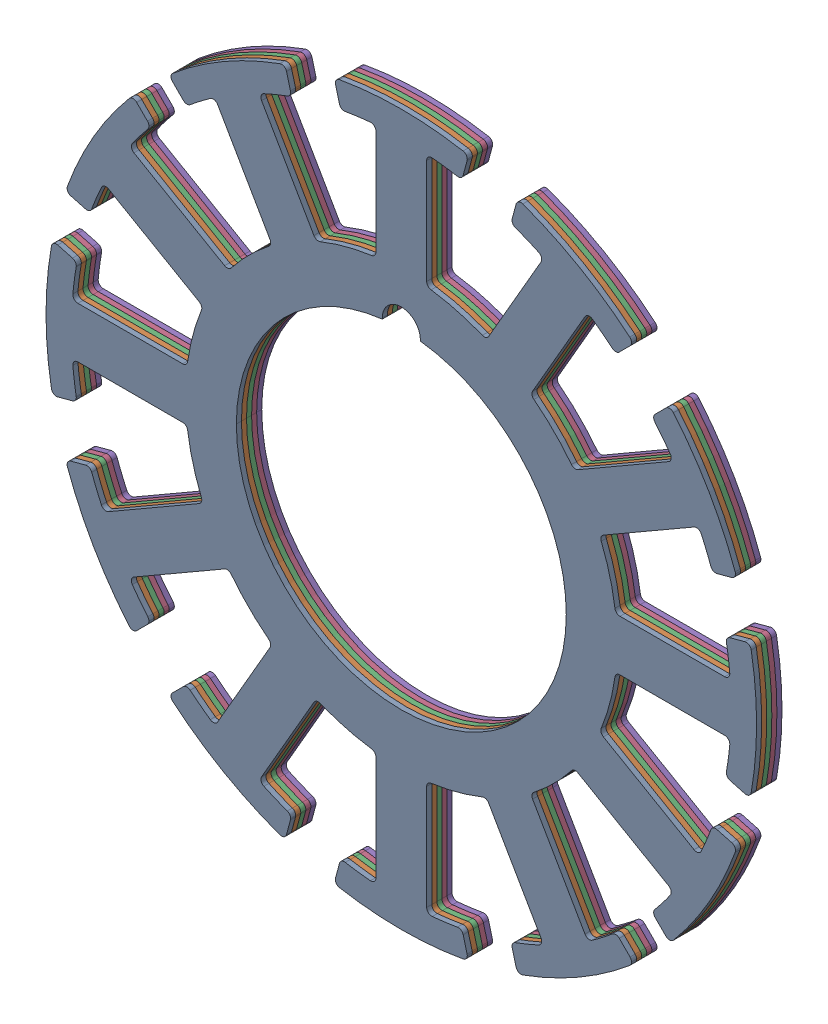
SolidWorks assembly 28x13x1mm-Stator.STEP, configuration Default. Lengths in mm.
Overall size (28 28 1).
5 component instances, 1 part files, 0 mates.
Components (placement in the parent):
- 28x13-Stator Plate.STEP-1: 28x13-Stator Plate.STEP [Default] at (-28.2175 12.5042 6.2948) size (28 28 0.2)
- 28x13-Stator Plate.STEP-2: 28x13-Stator Plate.STEP [Default] at (-28.2175 12.5042 6.0948) size (28 28 0.2)
- 28x13-Stator Plate.STEP-3: 28x13-Stator Plate.STEP [Default] at (-28.2175 12.5042 5.8948) size (28 28 0.2)
- 28x13-Stator Plate.STEP-4: 28x13-Stator Plate.STEP [Default] at (-28.2175 12.5042 5.6948) size (28 28 0.2)
- 28x13-Stator Plate.STEP-5: 28x13-Stator Plate.STEP [Default] at (-28.2175 12.5042 5.4948) size (28 28 0.2)
